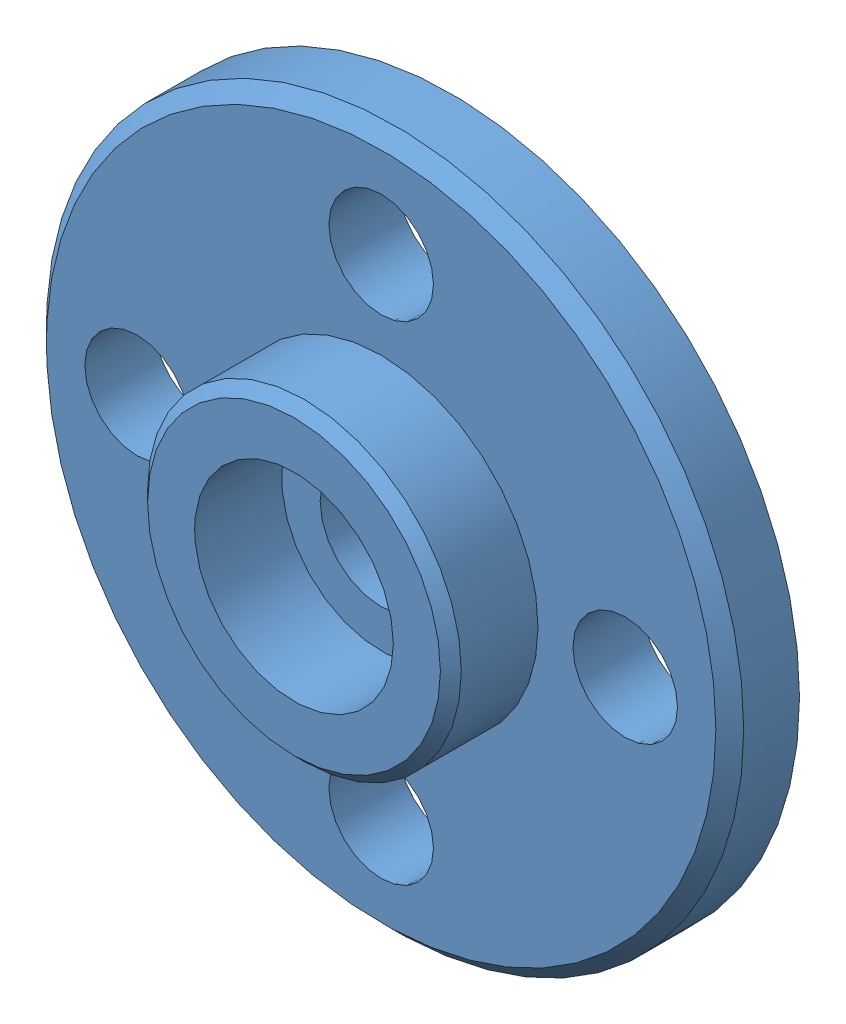
SolidWorks assembly Servo Hub v2, configuration Default. Lengths in mm.
Overall size (20 20 4.5).
2 component instances, 1 part files, 0 mates.
Components (placement in the parent):
- ServoHub v2.step-1: ServoHub v2.step [Default] at (5.0952 10.8538 14.0694) size (20 20 4.5)
  - ServoHub_1.step-1: ServoHub_1.step [Default] at origin size (20 20 4.5)
